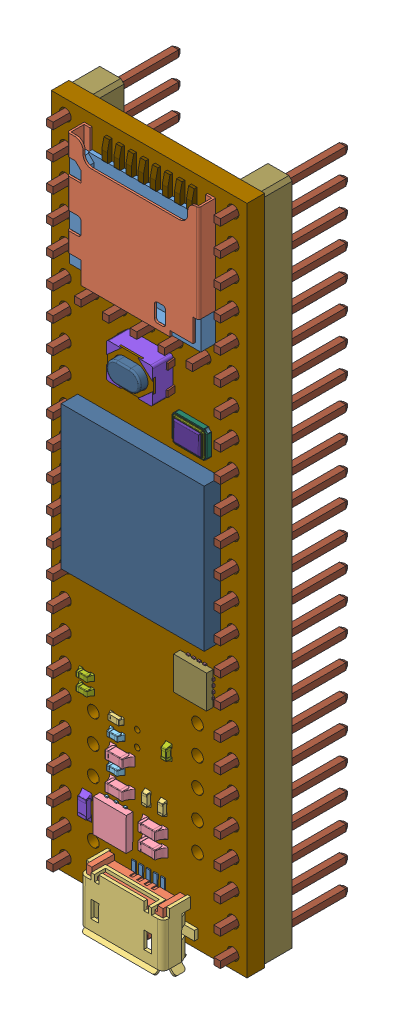
SolidWorks assembly Sparkfun_Teensy35_14056.step, configuration Default. Lengths in mm.
Overall size (17.78 62.36 13.14).
61 component instances, 30 part files, 0 mates.
Components (placement in the parent):
- micro_usb (1).step-1: micro_usb (1).step [Default] at (4.9268 4.2855 1.4822) x (0.999991 -0.004152 0) z (-0.004152 -0.999991 0) size (8.92 3.06 5.65)
  - Group#12 (1).step-1: Group#12 (1).step [Default] at (2.538 1.6565 1.0539) size (0.37 1.54 3.85)
  - micro_usb_plastic (1).step-1: micro_usb_plastic (1).step [Default] at (0.5522 0.3698 0.3039) size (6.98 2.05 3.55)
  - micro_usb_shell (1).step-1: micro_usb_shell (1).step [Default] at (0.2522 0.2178 0.3039) size (8.92 3.06 5.35)
  - Group#12 (1).step-2: Group#12 (1).step [Default] at (3.1965 1.6565 1.0539) size (0.37 1.54 3.85)
  - Group#12 (1).step-3: Group#12 (1).step [Default] at (3.8551 1.6565 1.0539) size (0.37 1.54 3.85)
  - Group#12 (1).step-4: Group#12 (1).step [Default] at (4.5137 1.6565 1.0539) size (0.37 1.54 3.85)
  - Group#12 (1).step-5: Group#12 (1).step [Default] at (5.1722 1.6565 1.0539) size (0.37 1.54 3.85)
- qfp16 v2 (1).step-1: qfp16 v2 (1).step [Default] at (5.9498 6.4523 1.6) x (-0.004152 -0.999991 0) z (0 0 1) size (3.2 3 0.65)
  - package.step-1: package.step [Default] at origin size (3 3 0.6)
  - lead (1).step-1: lead (1).step [Default] at origin size (3.2 1.95 0.15)
- wson-6 v3.step-1: wson-6 v3.step [Default] at (14.3092 31.5639 1.6) x (0.004152 0.999991 0) z (0 0 1) size (2.2 2 0.75)
  - Component28.step-1: Component28.step [Default] at origin size (2 2 0.7)
  - lead (2).step-1: lead (2).step [Default] at origin size (2.2 1.5 0.15)
- smt_tactile_button_2 v2.step-1: smt_tactile_button_2 v2.step [Default] at (9.002 44.1542 1.6) x (0.999991 -0.004152 0) z (0 0 1) size (4.63 3.2 2.5)
  - Component43.step-1: Component43.step [Default] at origin size (4.2 3.2 1.85)
  - Component44.step-1: Component44.step [Default] at origin size (4.2 3.2 0.15)
  - Component45.step-1: Component45.step [Default] at origin size (3.1 1.9 1.5)
  - Component46.step-1: Component46.step [Default] at origin size (4.63 2.7 0.73)
- qfp16 v2.step-1: qfp16 v2.step [Default] at (13.2506 21.3112 1.6) x (0.999991 -0.004152 0) z (0 0 1) size (3.2 3.2 0.65)
  - Component21.step-1: Component21.step [Default] at origin size (3 3 0.6)
  - lead.step-1: lead.step [Default] at origin size (3.2 3.2 0.15)
- crystal_dfn4 v8.step-1: crystal_dfn4 v8.step [Default] at (12.9489 40.4086 1.6) x (0.999991 -0.004152 0) z (0 0 1) size (3.2 2.5 0.72)
  - Component38.step-1: Component38.step [Default] at origin size (3.2 2.5 0.3)
  - Component39.step-1: Component39.step [Default] at origin size (3.2 2.5 0.4)
  - Component40.step-1: Component40.step [Default] at origin size (2.9 2.3 0.2)
  - Component41.step-1: Component41.step [Default] at origin size (2.53 1.93 0.22)
- HR5 DM3D Micro SD Card v4.step-1: HR5 DM3D Micro SD Card v4.step [Default] at (8.955 59.96 1.6) x (-1 0 0) z (0 1 0) size (11.95 1.55 11.45)
  - Pins.step-1: Pins.step [Default] at origin size (8.2 0.45 1.8)
    - Component2.step-1: Component2.step [Default] at (7.7 0 0) size (0.5 0.45 1.8)
    - Component2.step-2: Component2.step [Default] at origin size (0.5 0.45 1.8)
    - Component2.step-3: Component2.step [Default] at (4.4 0 0) size (0.5 0.45 1.8)
    - Component2.step-4: Component2.step [Default] at (1.1 0 0) size (0.5 0.45 1.8)
    - Component2.step-5: Component2.step [Default] at (5.5 0 0) size (0.5 0.45 1.8)
    - Component2.step-6: Component2.step [Default] at (6.6 0 0) size (0.5 0.45 1.8)
    - Component2.step-7: Component2.step [Default] at (3.3 0 0) size (0.5 0.45 1.8)
    - Component2.step-8: Component2.step [Default] at (2.2 0 0) size (0.5 0.45 1.8)
  - Base.step-1: Base.step [Default] at origin size (11.95 1.35 9.65)
  - Case.step-1: Case.step [Default] at origin size (11.95 1.55 11.45)
- diode_0402 v1.step-1: diode_0402 v1.step [Default] at (5.9836 14.5803 1.6) x (0.999991 -0.004152 0) z (0 0 1) size (1.27 0.6 0.35)
- cap0603_03 v3.step-1: cap0603_03 v3.step [Default] at (6.4446 9.3713 1.6) x (0.999991 -0.004152 0) z (0 0 1) size (2.33 0.91 0.82)
- cap0402 v2 (1).step-1: cap0402 v2 (1).step [Default] at (6.0039 13.361 1.6) x (0.999991 -0.004152 0) z (0 0 1) size (1.37 0.6 0.51)
- cap0402 v2 (1).step-2: cap0402 v2 (1).step [Default] at (5.9928 10.6686 1.6) x (0.999991 -0.004152 0) z (0 0 1) size (1.37 0.6 0.51)
- diode_0402 v1.step-2: diode_0402 v1.step [Default] at (8.7709 9.691 1.6) x (0.004152 0.999991 0) z (0 0 1) size (1.27 0.6 0.35)
- diode_0402 v1.step-3: diode_0402 v1.step [Default] at (10.2187 9.685 1.6) x (0.004152 0.999991 0) z (0 0 1) size (1.27 0.6 0.35)
- smt_led_0805 v2.step-1: smt_led_0805 v2.step [Default] at (3.1328 31.4833 1.6) x (0.999991 -0.004152 0) z (0 0 1) size (0.9 2 0.92)
- cap0402 v2.step-1: cap0402 v2.step [Default] at (10.6774 14.3109 1.6) x (0.004152 0.999991 0) z (0 0 1) size (1.37 0.6 0.51)
- cap0402 v2.step-2: cap0402 v2.step [Default] at (3.2189 15.5316 1.6) x (0.999991 -0.004152 0) z (0 0 1) size (1.37 0.6 0.51)
- cap0402 v2.step-3: cap0402 v2.step [Default] at (3.2237 16.6746 1.6) x (0.999991 -0.004152 0) z (0 0 1) size (1.37 0.6 0.51)
- cap0603_03 v3.step-2: cap0603_03 v3.step [Default] at (6.4552 11.9367 1.6) x (0.999991 -0.004152 0) z (0 0 1) size (2.33 0.91 0.82)
- cap0603_03 v3.step-3: cap0603_03 v3.step [Default] at (9.4289 6.2601 1.6) x (0.999991 -0.004152 0) z (0 0 1) size (2.33 0.91 0.82)
- cap0603_03 v3.step-4: cap0603_03 v3.step [Default] at (9.435 7.7333 1.6) x (0.999991 -0.004152 0) z (0 0 1) size (2.33 0.91 0.82)
- cap0603_03 v3.step-5: cap0603_03 v3.step [Default] at (3.0943 28.3083 1.6) x (0.004152 0.999991 0) z (0 0 1) size (2.33 0.91 0.82)
- diode_0402 v1.step-4: diode_0402 v1.step [Default] at (4.5797 31.07 1.6) x (0.004152 0.999991 0) z (0 0 1) size (1.27 0.6 0.35)
- cap0402 v2.step-4: cap0402 v2.step [Default] at (14.1981 29.2783 1.6) x (0.999991 -0.004152 0) z (0 0 1) size (1.37 0.6 0.51)
- cap0402 v2.step-5: cap0402 v2.step [Default] at (14.8222 27.6288 1.6) x (0.004152 0.999991 0) z (0 0 1) size (1.37 0.6 0.51)
- resistor_0603 v3.step-1: resistor_0603 v3.step [Default] at (3.2192 6.3271 1.6) x (0.004152 0.999991 0) z (0 0 1) size (2.3 0.91 0.45)
- Full Board.step-1: Full Board.step [Default] at origin size (17.78 60.96 1.6)
- Component37.step-1: Component37.step [Default] at origin size (13 13 1.5)
- Component38 (1).step-1: Component38 (1).step [Default] at origin size (15.8 59.02 11.7)
- Component39 (1).step-1: Component39 (1).step [Default] at origin size (17.78 60.96 2.5)
